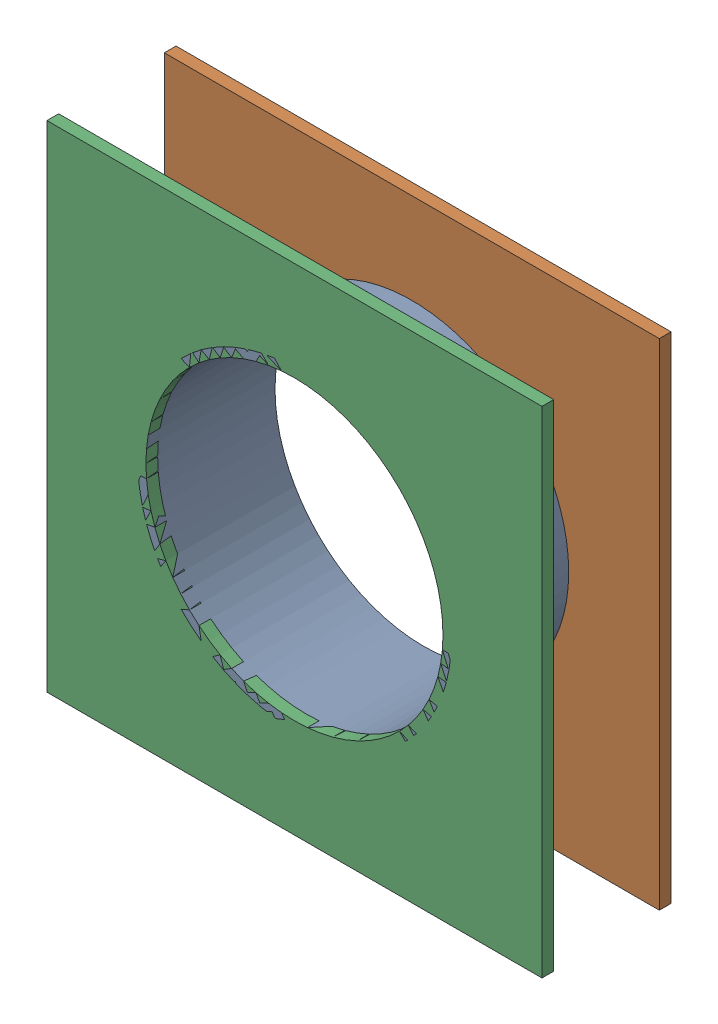
SolidWorks assembly Pad UART-1(13mm,43.4mm) on Multi-Layer, configuration Predeterminado. Lengths in mm.
Overall size (1.5 1.5 0.39).
6 component instances, 3 part files, 0 mates.
Components (placement in the parent):
- Pad Hole-1-1: Pad Hole-1 [Predeterminado] at (13 43.4 -0.4013) size (0.95 0.95 0.39)
  - Pad Hole-Part-1-1-1: Pad Hole-Part-1-1 [Predeterminado] at origin size (0.95 0.95 0.39)
- Pad Copper-2-1: Pad Copper-2 [Predeterminado] at (-68.317 -44.187 -0.4013) size (1.5 1.5 0.04)
  - Pad Copper-Part-1-2-1: Pad Copper-Part-1-2 [Predeterminado] at origin size (1.5 1.5 0.04)
- Pad Copper-3-1: Pad Copper-3 [Predeterminado] at (-68.317 -44.187 -0.0457) size (1.5 1.5 0.04)
  - Pad Copper-Part-1-3-1: Pad Copper-Part-1-3 [Predeterminado] at origin size (1.5 1.5 0.04)
